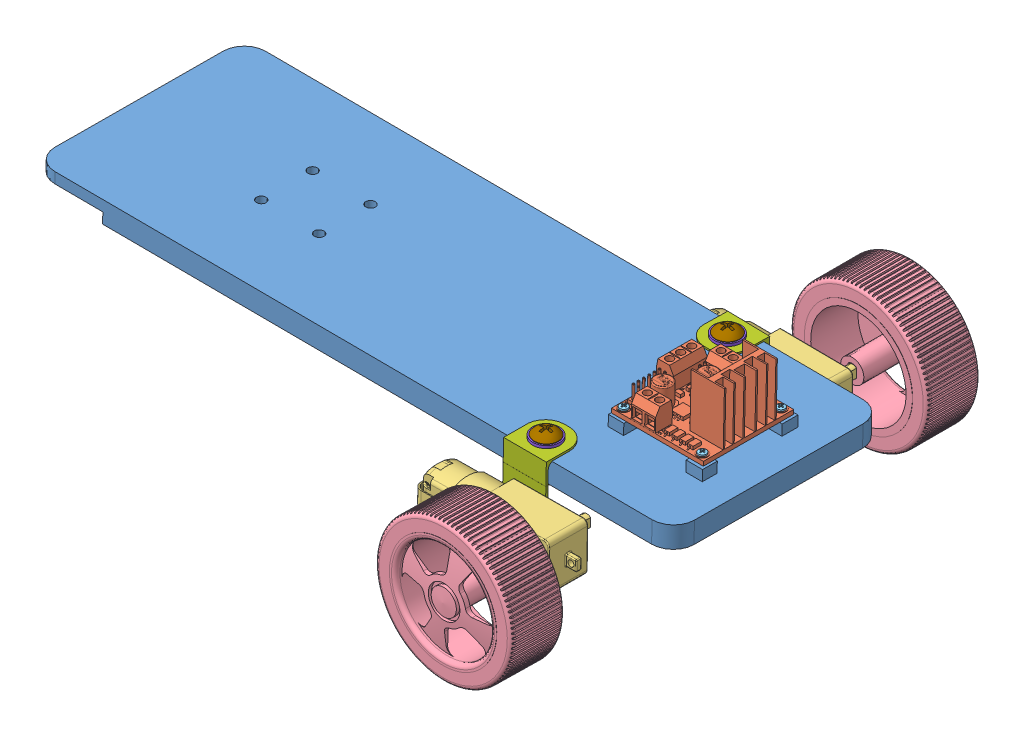
SolidWorks assembly Ensamblaje plataforma, configuration Default. Lengths in mm.
Overall size (300.72 90.04 222.49).
29 component instances, 12 part files, 49 mates.
Components (placement in the parent):
- Assem2^Ensamblaje plataforma-1: Assem2^Ensamblaje plataforma [Default] at (3.5691 4.6587 -10.9634) x (0.999927 -0.010646 -0.005731) z (0.005851 0.011291 0.999919) size (300 15 100) (virtual)
  - Plataforma base-1: Plataforma base [Default] at (153.6211 143.2192 210.7445) size (300 15 100)
- L298N Stepper Motor Driver (Red)-Part File_1-1: L298N Stepper Motor Driver (Red)-Part File_1 [Default] at (304.5056 161.89 180.8238) x (0.009007 0.011257 0.999896) z (-0.999903 0.010682 0.008887) size (43 28.01 43)
- motor-1: motor [Predeterminado] at (286.776 133.6833 234.5059) x (0.99996 -0.000052 -0.008955) z (0.008955 0.011258 0.999897) size (67.95 22.5 40)
- Tekerlek 66x26-1: Tekerlek 66x26 [Varsayılan] at (292.8516 134.075 278.8839) x (0.999384 -0.033984 0.008791) z (-0.034058 -0.999385 0.008386) size (65.22 28.28 65.22)
- Tekerlek 66x26-2: Tekerlek 66x26 [Varsayılan] at (292.332 131.9261 82.512) x (1 0 0) z (0 1 0) size (65.22 28.28 65.22)
- motor-2: motor [Predeterminado] at (286.6839 132.0528 109.0438) x (0.999961 0.000051 0.00887) z (-0.00887 0.011446 0.999895) size (67.95 22.5 40)
- binding head screw_ai-7: binding head screw_ai [CR-BHMS 0.073-64x0.5625x0.5625-N] at (285.8167 165.1182 162.2106) x (-0.010581 -0.99988 0.011352) z (0.010989 0.011236 0.999876) size (20.07 3.89 3.89)
- binding head screw_ai-8: binding head screw_ai [CR-BHMS 0.073-64x0.5625x0.5625-N] at (286.1534 165.539 199.5863) x (-0.010581 -0.99988 0.011352) z (0.010989 0.011236 0.999876) size (20.07 3.89 3.89)
- binding head screw_ai-9: binding head screw_ai [CR-BHMS 0.073-64x0.5625x0.5625-N] at (322.8917 165.1465 199.2597) x (-0.010581 -0.99988 0.011352) z (0.010989 0.011236 0.999876) size (20.07 3.89 3.89)
- binding head screw_ai-10: binding head screw_ai [CR-BHMS 0.073-64x0.75x0.75-N] at (322.555 164.7257 161.8841) x (-0.010581 -0.99988 0.011352) z (0.010989 0.011236 0.999876) size (20.07 3.89 3.89)
- machine screw nut hex_ai-2: machine screw nut hex_ai [MSHXNUT 0.073-64-S-N] at (286.129 163.2279 199.6125) x (0.999883 -0.010454 0.01119) z (-0.010581 -0.99988 0.011352) size (3.96 4.58 1.27)
- machine screw nut hex_ai-4: machine screw nut hex_ai [MSHXNUT 0.073-64-S-N] at (285.9274 144.1802 199.8288) x (0.999883 -0.010454 0.01119) z (-0.010581 -0.99988 0.011352) size (3.96 4.58 1.27)
- machine screw nut hex_ai-5: machine screw nut hex_ai [MSHXNUT 0.073-64-S-N] at (323.2059 145.6384 200.0499) x (0.999883 -0.010454 0.01119) z (-0.010581 -0.99988 0.011352) size (3.96 4.58 1.27)
- machine screw nut hex_ai-6: machine screw nut hex_ai [MSHXNUT 0.073-64-S-N] at (322.5051 160.0149 161.9376) x (0.999883 -0.010454 0.01119) z (-0.010581 -0.99988 0.011352) size (3.96 4.58 1.27)
- machine screw nut hex_ai-7: machine screw nut hex_ai [MSHXNUT 0.073-64-S-N] at (323.1662 145.2062 161.9421) x (0.999883 -0.010454 0.01119) z (-0.010581 -0.99988 0.011352) size (3.96 4.58 1.27)
- machine screw nut hex_ai-8: machine screw nut hex_ai [MSHXNUT 0.073-64-S-N] at (285.5907 143.7594 162.4531) x (0.999883 -0.010454 0.01119) z (-0.010581 -0.99988 0.011352) size (3.96 4.58 1.27)
- L bracket-1: L bracket [fillet] at (264.2721 158.8679 234.4238) x (-0.010581 -0.99988 0.011352) z (0.999904 -0.010681 -0.008834) size (40 20 20)
- L bracket-2: L bracket [fillet] at (284.165 157.2784 128.724) x (-0.010581 -0.99988 0.011352) z (-0.999905 0.010479 -0.00899) size (40 20 20)
- flat washer type a selected narrow_ai-3: flat washer type a selected narrow_ai [Selected Narrow FW 0.25] at (274.1842 158.648 224.3003) x (-0.010581 -0.99988 0.011352) z (-0.011352 0.011472 0.99987) size (1.24 12.7 12.7)
- flat washer type a selected narrow_ai-4: flat washer type a selected narrow_ai [Selected Narrow FW 0.25] at (274.074 157.4981 138.6693) x (-0.010581 -0.99988 0.011352) z (-0.011352 0.011472 0.99987) size (1.24 12.7 12.7)
- truss head screw_ai-5: truss head screw_ai [CR-THMS 0.19-24x0.75x0.75-N] at (274.229 162.8893 224.2521) x (-0.010581 -0.99988 0.011352) z (-0.011352 0.011472 0.99987) size (22 11.38 11.38)
- truss head screw_ai-6: truss head screw_ai [CR-THMS 0.19-24x0.75x0.75-N] at (274.1189 161.7394 138.6212) x (-0.010581 -0.99988 0.011352) z (-0.011352 0.011472 0.99987) size (22 11.38 11.38)
- flat washer type b regular_ai-5: flat washer type b regular_ai [Regular FW 0.086] at (273.6801 123.3206 130.0199) x (0.00887 -0.011446 -0.999895) z (0.999895 -0.011344 0.009) size (0.81 6.35 6.35)
- flat washer type b regular_ai-6: flat washer type b regular_ai [Regular FW 0.086] at (273.8727 141.5264 129.8132) x (0.00887 -0.011446 -0.999895) z (0.999895 -0.011344 0.009) size (0.81 6.35 6.35)
- flat washer type b wide_ai-3: flat washer type b wide_ai [Wide FW 0.086] at (274.2106 142.8791 233.5148) x (0.008955 0.011258 0.999897) z (-0.999897 -0.011157 0.00908) size (0.81 8.74 8.74)
- flat washer type b wide_ai-4: flat washer type b wide_ai [Wide FW 0.086] at (274.018 124.6733 233.7215) x (0.008955 0.011258 0.999897) z (-0.999897 -0.011157 0.00908) size (0.81 8.74 8.74)
- hex jam nut_ai-2: hex jam nut_ai [HJNUT 0.2500-20-D-N] at (274.0246 143.5656 224.4715) x (0.999889 -0.010461 0.010581) z (-0.010581 -0.99988 0.011352) size (11.11 12.83 4.14)
- hex jam nut_ai-3: hex jam nut_ai [HJNUT 0.2500-20-D-N] at (273.9163 142.5945 138.8385) x (0.999889 -0.010461 0.010581) z (-0.010581 -0.99988 0.011352) size (11.11 12.83 4.14)
Mates (geometry in assembly coordinates):
- Coincident12: coincident: point of assembly; point of assembly; moEndPointRef_w of Tekerlek 66x26-2; moEndPointRef_w of motor-2
- Coincident16: coincident: point of assembly; point of assembly; moEndPointRef_w of motor-1; moEndPointRef_w of Tekerlek 66x26-1
- Concentric2: concentric: cylinder of assembly; circle of assembly; cylinder of Assem2^Ensamblaje plataforma-1/Plataforma base-1 through (284.6715 56.8898 163.4394) axis (0.010581 0.99988 -0.011352) radius 1.8; circle of L298N Stepper Motor Driver (Red)-Part File_1-1
- Concentric7: concentric: cylinder of assembly; cylinder of assembly; cylinder of L298N Stepper Motor Driver (Red)-Part File_1-1 through (285.7803 161.6772 162.2497) axis (0.010581 0.99988 -0.011352) radius 1.75; cylinder of binding head screw_ai-7 through (286.0855 190.5151 161.9223) axis (0.010581 0.99988 -0.011352) radius 0.9271
- Coincident22: coincident: plane of assembly; plane of assembly; plane of L298N Stepper Motor Driver (Red)-Part File_1-1 through (288.3127 164.0214 159.6702) normal (0.010581 0.99988 -0.011352); plane of binding head screw_ai-7 through (286.7327 164.067 162.2124) normal (-0.010581 -0.99988 0.011352)
- Concentric8: concentric: cylinder of assembly; cylinder of assembly; cylinder of L298N Stepper Motor Driver (Red)-Part File_1-1 through (286.117 162.098 199.6253) axis (0.010581 0.99988 -0.011352) radius 1.75; cylinder of binding head screw_ai-8 through (286.4222 190.9359 199.2979) axis (0.010581 0.99988 -0.011352) radius 0.9271
- Coincident23: coincident: plane of assembly; plane of assembly; plane of L298N Stepper Motor Driver (Red)-Part File_1-1 through (288.6494 164.4422 197.0459) normal (0.010581 0.99988 -0.011352); plane of binding head screw_ai-8 through (287.0694 164.4878 199.588) normal (-0.010581 -0.99988 0.011352)
- Concentric9: concentric: cylinder of assembly; cylinder of assembly; cylinder of L298N Stepper Motor Driver (Red)-Part File_1-1 through (322.8553 161.7055 199.2988) axis (0.010581 0.99988 -0.011352) radius 1.75; cylinder of binding head screw_ai-9 through (323.1604 190.5435 198.9714) axis (0.010581 0.99988 -0.011352) radius 0.9271
- Coincident24: coincident: plane of assembly; plane of assembly; plane of L298N Stepper Motor Driver (Red)-Part File_1-1 through (325.3876 164.0497 196.7193) normal (0.010581 0.99988 -0.011352); plane of binding head screw_ai-9 through (323.8076 164.0953 199.2615) normal (-0.010581 -0.99988 0.011352)
- Concentric10: concentric: cylinder of assembly; cylinder of assembly; cylinder of L298N Stepper Motor Driver (Red)-Part File_1-1 through (322.5186 161.2847 161.9232) axis (0.010581 0.99988 -0.011352) radius 1.75; cylinder of binding head screw_ai-10 through (322.8237 190.1227 161.5958) axis (0.010581 0.99988 -0.011352) radius 0.9271
- Coincident25: coincident: plane of assembly; plane of assembly; plane of L298N Stepper Motor Driver (Red)-Part File_1-1 through (325.0509 163.629 159.3437) normal (0.010581 0.99988 -0.011352); plane of binding head screw_ai-10 through (323.471 163.6745 161.8859) normal (-0.010581 -0.99988 0.011352)
- Concentric111: concentric: cone of assembly; cylinder of assembly; cone of binding head screw_ai-8 through (286.1424 164.4977 199.5981) axis (0.010581 0.99988 -0.011352); cylinder of machine screw nut hex_ai-2 through (286.3939 188.2624 199.3283) axis (-0.010581 -0.99988 0.011352) radius 0.9271
- Coincident261: coincident: plane of assembly; plane of assembly; plane of binding head screw_ai-8 through (287.0694 164.4878 199.588) normal (-0.010581 -0.99988 0.011352); plane of machine screw nut hex_ai-2 through (286.1171 164.5239 201.8855) normal (0.010581 0.99988 -0.011352)
- Concentric12: concentric: cylinder of assembly; cylinder of assembly; cylinder of L298N Stepper Motor Driver (Red)-Part File_1-1 through (286.117 162.098 199.6253) axis (0.010581 0.99988 -0.011352) radius 1.75; cylinder of machine screw nut hex_ai-4 through (286.1923 169.2146 199.5445) axis (-0.010581 -0.99988 0.011352) radius 0.9271
- Coincident27: coincident: plane of assembly; plane of assembly; plane of binding head screw_ai-8 through (286.8678 145.4401 199.8043) normal (-0.010581 -0.99988 0.011352); plane of machine screw nut hex_ai-4 through (285.9155 145.4762 202.1017) normal (0.010581 0.99988 -0.011352)
- Concentric13: concentric: cylinder of assembly; cylinder of assembly; cylinder of Assem2^Ensamblaje plataforma-1/Plataforma base-1 through (322.2671 56.9191 201.0572) axis (0.010581 0.99988 -0.011352) radius 1.8; cylinder of machine screw nut hex_ai-5 through (323.4708 170.6729 199.7657) axis (-0.010581 -0.99988 0.011352) radius 0.9271
- Coincident28: coincident: plane of assembly; plane of assembly; plane of Assem2^Ensamblaje plataforma-1/Plataforma base-1 through (159.9274 148.6047 197.2579) normal (-0.010581 -0.99988 0.011352); plane of machine screw nut hex_ai-5 through (323.194 146.9345 202.3229) normal (0.010581 0.99988 -0.011352)
- Concentric14: concentric: cylinder of assembly; cylinder of assembly; cylinder of binding head screw_ai-10 through (322.8237 190.1227 161.5958) axis (0.010581 0.99988 -0.011352) radius 0.9271; cylinder of machine screw nut hex_ai-6 through (322.7701 185.0494 161.6534) axis (-0.010581 -0.99988 0.011352) radius 0.9271
- Coincident29: coincident: plane of assembly; plane of assembly; plane of L298N Stepper Motor Driver (Red)-Part File_1-1 through (319.966 161.2833 159.4159) normal (-0.010581 -0.99988 0.011352); plane of machine screw nut hex_ai-6 through (322.4933 161.311 164.2106) normal (0.010581 0.99988 -0.011352)
- Concentric15: concentric: cylinder of assembly; cylinder of assembly; cylinder of Assem2^Ensamblaje plataforma-1/Plataforma base-1 through (322.2273 56.4869 162.9494) axis (0.010581 0.99988 -0.011352) radius 1.8; cylinder of machine screw nut hex_ai-7 through (323.4311 170.2407 161.6578) axis (-0.010581 -0.99988 0.011352) radius 0.9271
- Coincident30: coincident: plane of assembly; plane of assembly; plane of Assem2^Ensamblaje plataforma-1/Plataforma base-1 through (159.9274 148.6047 197.2579) normal (-0.010581 -0.99988 0.011352); plane of machine screw nut hex_ai-7 through (323.1543 146.5023 164.2151) normal (0.010581 0.99988 -0.011352)
- Concentric16: concentric: cylinder of assembly; cylinder of assembly; cylinder of L298N Stepper Motor Driver (Red)-Part File_1-1 through (285.7803 161.6772 162.2497) axis (0.010581 0.99988 -0.011352) radius 1.75; cylinder of machine screw nut hex_ai-8 through (285.8556 168.7939 162.1689) axis (-0.010581 -0.99988 0.011352) radius 0.9271
- Coincident31: coincident: plane of assembly; plane of assembly; plane of binding head screw_ai-7 through (286.5312 145.0193 162.4286) normal (-0.010581 -0.99988 0.011352); plane of machine screw nut hex_ai-8 through (285.5788 145.0555 164.7261) normal (0.010581 0.99988 -0.011352)
- Concentric21: concentric: circle of assembly; circle of assembly; circle of Assem2^Ensamblaje plataforma-1/Plataforma base-1; circle of L bracket-1
- Coincident33: coincident: circle of assembly; circle of assembly; circle of motor-1; circle of L bracket-1
- Coincident37: coincident: plane of assembly; line of assembly; plane of Assem2^Ensamblaje plataforma-1/Plataforma base-1 through (160.0861 163.6028 197.0876) normal (0.010581 0.99988 -0.011352); line of L298N Stepper Motor Driver (Red)-Part File_1-1 through (326.1971 161.9023 202.1305) axis (-0.999903 0.010682 0.008887)
- Concentric25: concentric: cylinder of assembly; circle of assembly; cylinder of Assem2^Ensamblaje plataforma-1/Plataforma base-1 through (273.7485 126.7366 139.0186) axis (0.010581 0.99988 -0.011352) radius 5.0077; circle of L bracket-2
- Coincident42: coincident: plane of assembly; line of assembly; plane of Assem2^Ensamblaje plataforma-1/Plataforma base-1 through (160.0861 163.6028 197.0876) normal (0.010581 0.99988 -0.011352); line of L298N Stepper Motor Driver (Red)-Part File_1-1 through (326.1971 161.9023 202.1305) axis (-0.999903 0.010682 0.008887)
- Concentric26: concentric: circle of assembly; circle of assembly; circle of motor-2; circle of L bracket-2
- Concentric281: concentric: cylinder of assembly; cylinder of assembly; cylinder of L bracket-1 through (274.0783 148.6492 224.4138) axis (0.010581 0.99988 -0.011352) radius 5.0147; cylinder of flat washer type a selected narrow_ai-3 through (274.5537 193.5688 223.9038) axis (0.010581 0.99988 -0.011352) radius 3.175
- Coincident461: coincident: plane of assembly; plane of assembly; plane of L bracket-1 through (284.2701 158.6542 234.2472) normal (0.010581 0.99988 -0.011352); plane of flat washer type a selected narrow_ai-3 through (277.3588 158.6149 224.3367) normal (-0.010581 -0.99988 0.011352)
- Concentric29: concentric: cylinder of assembly; cylinder of assembly; cylinder of L bracket-2 through (273.9682 147.4993 138.7828) axis (0.010581 0.99988 -0.011352) radius 5.0147; cylinder of flat washer type a selected narrow_ai-4 through (274.4435 192.4189 138.2728) axis (0.010581 0.99988 -0.011352) radius 3.175
- Coincident47: coincident: plane of assembly; plane of assembly; plane of L bracket-2 through (264.1669 157.488 128.5442) normal (0.010581 0.99988 -0.011352); plane of flat washer type a selected narrow_ai-4 through (277.2486 157.465 138.7057) normal (-0.010581 -0.99988 0.011352)
- Concentric31: concentric: cylinder of assembly; cylinder of assembly; cylinder of L bracket-1 through (274.0783 148.6492 224.4138) axis (0.010581 0.99988 -0.011352) radius 5.0147; cylinder of truss head screw_ai-5 through (274.4978 188.2863 223.9638) axis (0.010581 0.99988 -0.011352) radius 5.6896
- Coincident48: coincident: plane of assembly; plane of assembly; plane of flat washer type a selected narrow_ai-3 through (280.5466 159.8261 224.359) normal (0.010581 0.99988 -0.011352); plane of truss head screw_ai-5 through (276.61 159.8673 224.3138) normal (-0.010581 -0.99988 0.011352)
- Concentric32: concentric: cylinder of assembly; cylinder of assembly; cylinder of L bracket-2 through (273.9682 147.4993 138.7828) axis (0.010581 0.99988 -0.011352) radius 5.0147; cylinder of truss head screw_ai-6 through (274.3876 187.1364 138.3328) axis (0.010581 0.99988 -0.011352) radius 5.6896
- Coincident49: coincident: plane of assembly; plane of assembly; plane of flat washer type a selected narrow_ai-4 through (280.4364 158.6762 138.728) normal (0.010581 0.99988 -0.011352); plane of truss head screw_ai-6 through (276.4999 158.7174 138.6829) normal (-0.010581 -0.99988 0.011352)
- Concentric38: concentric: cylinder of assembly; cylinder of assembly; cylinder of L bracket-2 through (273.9462 122.9772 100.023) axis (-0.00887 0.011446 0.999895) radius 1.5; cylinder of flat washer type b regular_ai-5 through (273.3703 123.7204 164.9412) axis (-0.00887 0.011446 0.999895) radius 1.1938
- Coincident55: coincident: plane of assembly; plane of assembly; plane of L bracket-2 through (264.1474 156.4996 129.5555) normal (-0.00887 0.011446 0.999895); plane of flat washer type b regular_ai-5 through (273.6938 124.5143 130.0063) normal (0.00887 -0.011446 -0.999895)
- Concentric39: concentric: cylinder of assembly; cylinder of assembly; cylinder of L bracket-2 through (273.9614 141.4119 119.8142) axis (-0.00887 0.011446 0.999895) radius 1.5; cylinder of flat washer type b regular_ai-6 through (273.5629 141.9262 164.7345) axis (-0.00887 0.011446 0.999895) radius 1.1938
- Coincident56: coincident: plane of assembly; plane of assembly; plane of L bracket-2 through (264.1474 156.4996 129.5555) normal (-0.00887 0.011446 0.999895); plane of flat washer type b regular_ai-6 through (273.8864 142.7201 129.7996) normal (0.00887 -0.011446 -0.999895)
- Concentric47: concentric: cylinder of assembly; cylinder of assembly; cylinder of L bracket-1 through (274.3002 142.9916 243.5137) axis (-0.008955 -0.011258 -0.999897) radius 1.5; cylinder of flat washer type b wide_ai-3 through (273.8979 142.4859 198.5934) axis (-0.008955 -0.011258 -0.999897) radius 1.1938
- Coincident64: coincident: plane of assembly; plane of assembly; plane of L bracket-1 through (284.2506 157.6431 233.2586) normal (-0.008955 -0.011258 -0.999897); plane of flat washer type b wide_ai-3 through (274.1972 144.0727 233.5014) normal (0.008955 0.011258 0.999897)
- Concentric48: concentric: cylinder of assembly; cylinder of assembly; cylinder of L bracket-1 through (274.2866 125.011 263.7184) axis (-0.008955 -0.011258 -0.999897) radius 1.5; cylinder of flat washer type b wide_ai-4 through (273.7052 124.2801 198.8001) axis (-0.008955 -0.011258 -0.999897) radius 1.1938
- Coincident65: coincident: plane of assembly; plane of assembly; plane of L bracket-1 through (284.2506 157.6431 233.2586) normal (-0.008955 -0.011258 -0.999897); plane of flat washer type b wide_ai-4 through (274.0045 125.8669 233.7081) normal (0.008955 0.011258 0.999897)
- Concentric49: concentric: cylinder of assembly; cylinder of assembly; cylinder of Assem2^Ensamblaje plataforma-1/Plataforma base-1 through (273.8567 127.7077 224.6515) axis (0.010581 0.99988 -0.011352) radius 5.0077; cylinder of hex jam nut_ai-2 through (274.2895 168.6001 224.1873) axis (-0.010581 -0.99988 0.011352) radius 3.175
- Coincident66: coincident: plane of assembly; plane of assembly; plane of Assem2^Ensamblaje plataforma-1/Plataforma base-1 through (159.9274 148.6047 197.2579) normal (-0.010581 -0.99988 0.011352); plane of hex jam nut_ai-2 through (262.9571 147.8215 224.3069) normal (0.010581 0.99988 -0.011352)
- Concentric50: concentric: cylinder of assembly; cylinder of assembly; cylinder of Assem2^Ensamblaje plataforma-1/Plataforma base-1 through (273.7485 126.7366 139.0186) axis (0.010581 0.99988 -0.011352) radius 5.0077; cylinder of hex jam nut_ai-3 through (274.1812 167.629 138.5543) axis (-0.010581 -0.99988 0.011352) radius 3.175
- Coincident67: coincident: plane of assembly; plane of assembly; plane of Assem2^Ensamblaje plataforma-1/Plataforma base-1 through (159.9274 148.6047 197.2579) normal (-0.010581 -0.99988 0.011352); plane of hex jam nut_ai-3 through (262.8488 146.8504 138.6739) normal (0.010581 0.99988 -0.011352)
